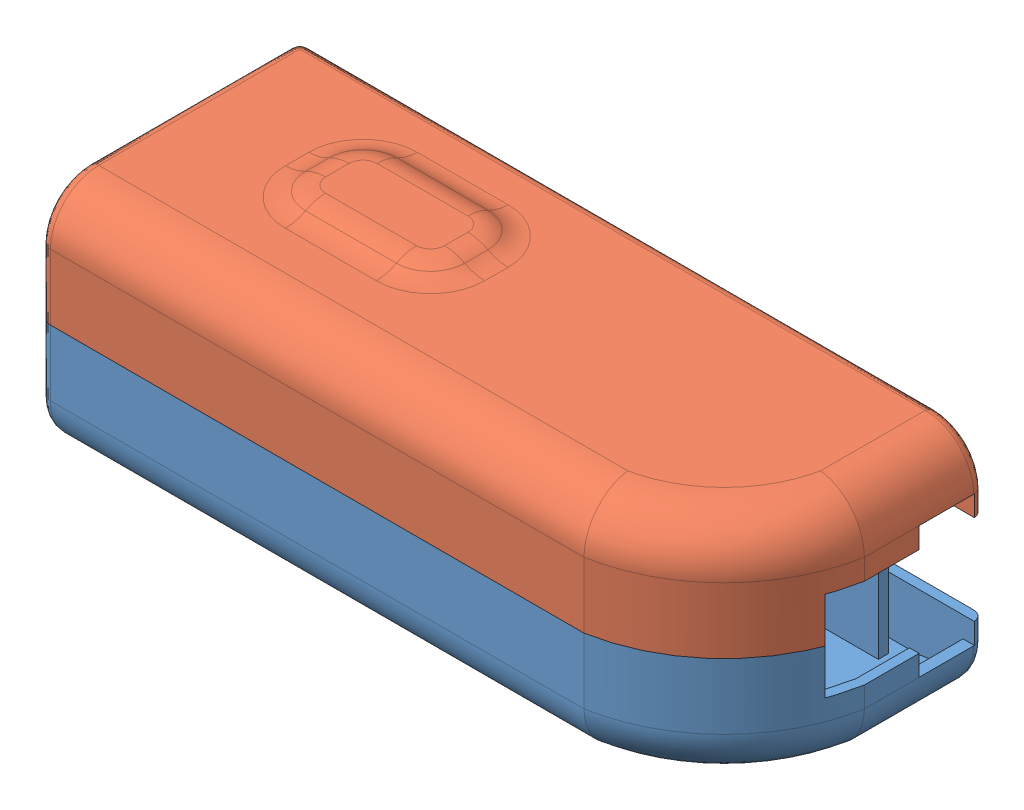
SolidWorks assembly Montagem, configuration Default. Lengths in mm.
Overall size (99 36 37.6).
2 component instances, 2 part files, 3 mates.
Components (placement in the parent):
- Esquerda-1: Esquerda [Default] at (-146.1049 -20.1308 66.2468) size (99 27.7 37.6)
- Direita final-1: Direita final [Default] at (-146.1049 9.2692 66.2468) x (1 0 0) z (0 0 -1) size (99 20.5 37.6)
Mates (geometry in assembly coordinates):
- Coincident4: coincident anti-aligned: plane of Esquerda-1 through (-78.7526 -5.4308 54.899) normal (0 1 0); plane of Direita final-1 through (-78.7526 -5.4308 54.899) normal (0 -1 0)
- Concentric1: concentric aligned: circle of Esquerda-1; circle of Direita final-1
- Concentric2: concentric aligned: circle of Esquerda-1; circle of Direita final-1
